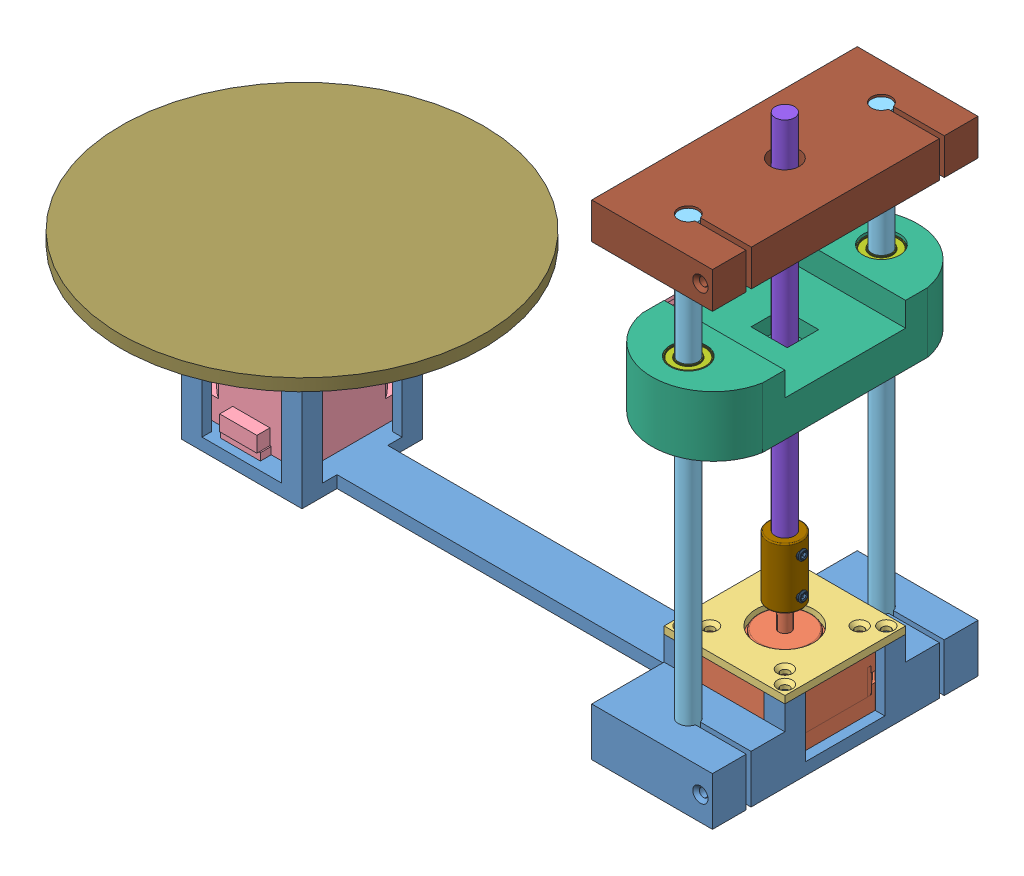
SolidWorks assembly Scanner, configuration Default. Lengths in mm.
Overall size (300.01 217.3 150).
24 component instances, 13 part files, 25 mates.
Components (placement in the parent):
- Base-1: Base [Default] at (-31.3473 98.2493 211.1868) size (250.01 46 110)
- Motor_small_and_plate-1: Motor_small_and_plate [Default] at (156.4594 165.1092 177.3057) x (1 0 0) z (0 -1 0) size (50 50 51.3)
  - NEMA_17_PHB42S28-406A v2-1: NEMA_17_PHB42S28-406A v2 [Default] at (16.9071 48.8811 -1035.1401) size (42.3 42.3 51.3)
  - Plate-1: Plate [Default] at (12.2071 33.8811 36.8599) x (0 -1 0) z (1 0 0) size (50 3 50)
- Motor_big_and_plate-1: Motor_big_and_plate [Default] at (24.0692 163.9676 219.0838) x (1 0 0) z (0 1 0) size (50 51.4 61)
  - NEMA17-42A0C-1: NEMA17-42A0C [Default] at (-55.4166 7.897 -19.7183) size (42 47.4 61)
    - NEMA17-42A0C.step-1: NEMA17-42A0C.step [Default] at origin size (42 47.4 61)
      - NEMA17-42A02C-Body.step-1: NEMA17-42A02C-Body.step [Default] at origin size (42 47.4 61)
  - Plate-2: Plate [Default] at (-55.4166 7.897 -19.7183) x (0 1 0) z (1 0 0) size (50 3 50)
- Axle-1: Axle [Default] at (168.6596 98.2493 251.1868) size (8 200 8)
- Axle-2: Axle [Default] at (168.6596 98.2493 171.1868) size (8 200 8)
- Sensor_Mount-1: Sensor_Mount [Default] at (168.6665 248.037 211.1868) x (0 -1 0) z (0 0 1) size (25 50 110)
- 3.Linear Bearing-LM8UU.step-1: 3.Linear Bearing-LM8UU.step [Default] at (168.6596 247.037 171.1868) x (1 0 0) z (0 -1 0) size (15.01 15 24)
- 3.Linear Bearing-LM8UU.step-2: 3.Linear Bearing-LM8UU.step [Default] at (168.6596 224.037 251.1868) x (1 0 0) z (0 1 0) size (15.01 15 24)
- Threaded_rod_8mm-1: Threaded_rod_8mm [Default] at (168.6665 165.5493 211.1868) size (8 150 8)
- Shaft Coupler_5 - 8 mm.step-1: Shaft Coupler_5 - 8 mm.step [Default] at (168.6665 140.5493 211.1868) x (0 1 0) z (0 0 1) size (25 16.01 14)
  - Shaft Coupler.step-1: Shaft Coupler.step [Default] at origin size (25 14.04 14)
  - M4 x 4mm Cup-Point Set Screw.step-1: M4 x 4mm Cup-Point Set Screw.step [Default] at (5.05 6.3306 0) x (1 0 0) z (0 1 0) size (5.53 5.51 4.01)
  - M4 x 4mm Cup-Point Set Screw.step-2: M4 x 4mm Cup-Point Set Screw.step [Default] at (19.95 6.3306 0) x (1 0 0) z (0 1 0) size (5.53 5.51 4.01)
  - M4 x 4mm Cup-Point Set Screw.step-3: M4 x 4mm Cup-Point Set Screw.step [Default] at (5.05 -6.3306 0) x (1 0 0) z (0 -1 0) size (5.53 5.51 4.01)
  - M4 x 4mm Cup-Point Set Screw.step-4: M4 x 4mm Cup-Point Set Screw.step [Default] at (19.95 -6.3306 0) x (1 0 0) z (0 -1 0) size (5.53 5.51 4.01)
- Retention_hat-1: Retention_hat [Default] at (168.6665 284.0704 211.1868) x (0 0 -1) z (1 0 0) size (110 15 50)
- Scanner_plate-1: Scanner_plate [Default] at (-31.3473 173.2493 211.1868) x (-1 0 0) z (0 0 1) size (150 20 150)
- Long Range SHARP IR Sensors - #GP2Y0A21YK0F.step-1: Long Range SHARP IR Sensors - #GP2Y0A21YK0F.step [Default] at (149.9665 237.3254 225.4368) x (0 0 -1) z (-1 0 0) size (44.5 18.9 15.2)
Mates (geometry in assembly coordinates):
- Coincident1: coincident aligned: plane of Base-1 through (193.6665 103.2493 236.1868) normal (1 0 0); plane of Motor_small_and_plate-1/Plate-1 through (193.6665 131.2493 186.1868) normal (1 0 0)
- Coincident2: coincident aligned: plane of Base-1 through (193.6665 103.2493 186.1868) normal (0 0 -1); plane of Motor_small_and_plate-1/Plate-1 through (193.6665 131.2493 186.1868) normal (0 0 -1)
- Coincident3: coincident anti-aligned: plane of Base-1 through (-31.3473 128.2493 211.1868) normal (0 1 0); plane of Motor_small_and_plate-1/Plate-1 through (168.6665 128.2493 211.1868) normal (0 -1 0)
- Coincident4: coincident aligned: plane of Base-1 through (-6.3473 103.2493 236.1868) normal (0 0 1); plane of Motor_big_and_plate-1/Plate-2 through (-6.3473 147.2493 236.1868) normal (0 0 1)
- Coincident5: coincident aligned: plane of Base-1 through (-56.3473 103.2493 236.1868) normal (-1 0 0); plane of Motor_big_and_plate-1/Plate-2 through (-56.3473 147.2493 186.1868) normal (-1 0 0)
- Coincident6: coincident anti-aligned: plane of Base-1 through (-31.3473 144.2493 211.1868) normal (0 1 0); plane of Motor_big_and_plate-1/Plate-2 through (-31.3473 144.2493 211.1868) normal (0 -1 0)
- Concentric1: concentric aligned: circle of Base-1; circle of Axle-1
- Coincident8: coincident aligned: plane of Base-1 through (-31.3473 98.2493 211.1868) normal (0 -1 0); plane of Axle-1 through (168.6596 98.2493 251.1868) normal (0 -1 0)
- Concentric2: concentric aligned: circle of Base-1; circle of Axle-2
- Coincident9: coincident aligned: plane of Base-1 through (-31.3473 98.2493 211.1868) normal (0 -1 0); plane of Axle-2 through (168.6596 98.2493 171.1868) normal (0 -1 0)
- Coincident11: coincident aligned: plane of Base-1 through (193.6665 103.2493 236.1868) normal (1 0 0); plane of Sensor_Mount-1 through (193.6665 223.037 156.1868) normal (1 0 0)
- Concentric3: concentric aligned: circle of Sensor_Mount-1; circle of 3.Linear Bearing-LM8UU.step-1
- Coincident15: coincident aligned: plane of Sensor_Mount-1 through (168.6665 223.037 211.1868) normal (0 -1 0); plane of 3.Linear Bearing-LM8UU.step-1 through (168.6596 223.037 171.1868) normal (0 -1 0)
- Concentric4: concentric aligned: circle of Sensor_Mount-1; circle of 3.Linear Bearing-LM8UU.step-2
- Coincident16: coincident aligned: plane of Sensor_Mount-1 through (168.6665 248.037 211.1868) normal (0 1 0); plane of 3.Linear Bearing-LM8UU.step-2 through (168.6596 248.037 251.1868) normal (0 1 0)
- Concentric6: concentric aligned: cylinder of Motor_small_and_plate-1/NEMA_17_PHB42S28-406A v2-1 through (168.6665 130.2493 211.1868) axis (0 1 0) radius 2.5; circle of Shaft Coupler_5 - 8 mm.step-1/Shaft Coupler.step-1
- Coincident18: coincident aligned: plane of Motor_small_and_plate-1/NEMA_17_PHB42S28-406A v2-1 through (168.6665 152.5493 211.1868) normal (0 1 0); plane of Shaft Coupler_5 - 8 mm.step-1/Shaft Coupler.step-1 through (168.6665 152.5493 211.1868) normal (0 1 0)
- Coincident19: coincident anti-aligned: circle of Threaded_rod_8mm-1; circle of Shaft Coupler_5 - 8 mm.step-1/Shaft Coupler.step-1
- Concentric7: concentric aligned: circle of Threaded_rod_8mm-1; circle of Retention_hat-1
- Parallel1: parallel anti-aligned: plane of Base-1 through (193.6665 118.2493 156.1868) normal (0 0 -1); plane of Retention_hat-1 through (193.6665 299.0704 266.1868) normal (0 0 1)
- Concentric9: concentric anti-aligned: circle of Motor_big_and_plate-1/NEMA17-42A0C-1/NEMA17-42A0C.step-1/NEMA17-42A02C-Body.step-1; circle of Scanner_plate-1
- Coincident21: coincident anti-aligned: plane of Motor_big_and_plate-1/NEMA17-42A0C-1/NEMA17-42A0C.step-1/NEMA17-42A02C-Body.step-1 through (-31.3473 168.2493 211.1868) normal (0 1 0); plane of Scanner_plate-1 through (-31.3473 168.2493 211.1868) normal (0 -1 0)
- Concentric10: concentric aligned: circle of Sensor_Mount-1; circle of Long Range SHARP IR Sensors - #GP2Y0A21YK0F.step-1
- Parallel2: parallel aligned: plane of Sensor_Mount-1 through (193.6665 238.037 186.1868) normal (0 1 0); plane of Long Range SHARP IR Sensors - #GP2Y0A21YK0F.step-1 through (104.7785 237.3254 225.4368) normal (0 1 0)
- Coincident23: coincident anti-aligned: plane of Sensor_Mount-1 through (143.6665 223.037 156.1868) normal (-1 0 0); plane of Long Range SHARP IR Sensors - #GP2Y0A21YK0F.step-1 through (143.6665 231.0523 192.1868) normal (1 0 0)
